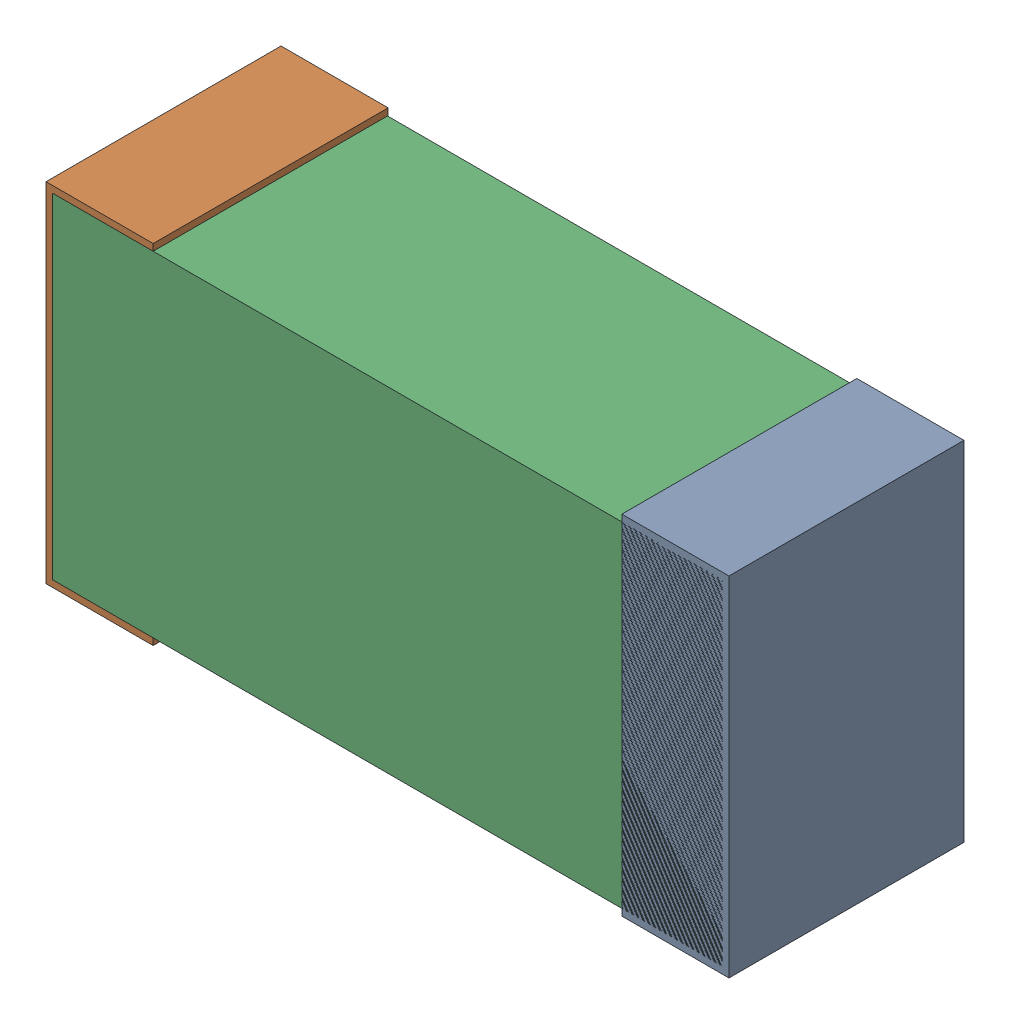
SolidWorks assembly C26, configuration Default. Lengths in mm.
Overall size (1.02 0.52 0.35).
6 component instances, 2 part files, 0 mates.
Components (placement in the parent):
- 870940480-1: 870940480 [Default] at (9.878 24.077 -1.9516) size (0.16 0.52 0.35)
  - Extruded-1: Extruded [Default] at origin size (0.16 0.52 0.35)
- 870940480-2: 870940480 [Default] at (9.018 24.077 -1.9516) size (0.16 0.52 0.35)
  - Extruded-1: Extruded [Default] at origin size (0.16 0.52 0.35)
- 870940640-1: 870940640 [Default] at (9.448 24.077 -1.9506) size (1 0.5 0.35)
  - Extruded_2-1: Extruded_2 [Default] at origin size (1 0.5 0.35)
